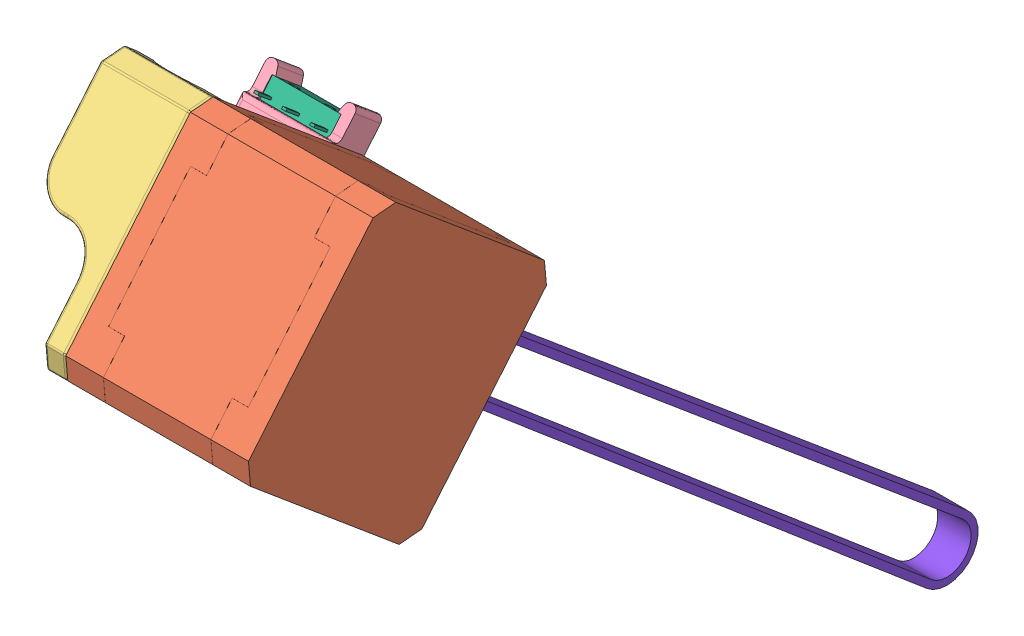
SolidWorks assembly X Stepper Assembly, configuration Default. Lengths in mm.
Overall size (57.11 160.28 210.05).
15 component instances, 12 part files, 20 mates.
Components (placement in the parent):
- Timing Gear 15 touth MXL MP-1: Timing Gear 15 touth MXL MP [Valor predeterminado] at origin size (14.3 14.8 14.8)
- Steper Motor 34mm-1: Steper Motor 34mm [Default] at (53 0 0) x (0 0.766371 -0.642398) z (-1 0 0) size (42.1 42.1 49.5)
- X Motor atachment mirror3-1: X Motor atachment mirror3 [Valor predeterminado] at (19 -41.7303 -84.9055) x (0 -0.642398 -0.766371) z (-1 0 0) size (11.1 84.26 17.12)
- X Bridge spacer for endstop-1: X Bridge spacer for endstop [Valor predeterminado] at (19 -20.6422 -23.8215) x (0 0.642398 0.766371) z (-1 0 0) size (9.2 14.43 16.74)
- Endstop Assembly - small-1: Endstop Assembly - small [Default] at (5.9214 9.6342 -22.8905) x (-1 0 0) z (0 -0.766371 0.642398) size (13.8 11.8 5.71)
  - Endstop Actuator 1-1: Endstop Actuator 1 [Default] at (-9.3436 7.5264 -0.1798) size (12.8 2.57 3.6)
  - Enstop Base 1-1: Enstop Base 1 [Default] at (-1.4636 2.6194 0.1552) size (12.83 9.86 5.71)
- X Bridge spacer-1: X Bridge spacer [Valor predeterminado] at (19 -3.8335 11.8254) x (0 -0.132847 -0.991137) z (-1 0 0) size (6.2 6.2 16.74)
- X Belt (MXL)-1: X Belt (MXL) [Default] at (10.1 -178.8916 299.2878) x (0 0.762669 -0.646788) z (1 0 0) size (11.6 200.95 6.2)
- pan head cross recess screw_iso1-1: pan head cross recess screw_iso1 [ISO 7045 - M3 x 25 - Z --- 25N] at (-4.14 -21.8359 -1.9216) x (1 0 0) z (0 0.424638 0.905363) size (27.35 5.6 5.6)
- pan head cross recess screw_iso1-2: pan head cross recess screw_iso1 [ISO 7045 - M3 x 25 - Z --- 25N] at (-4.14 1.9216 -21.8359) x (1 0 0) z (0 0.386405 -0.922329) size (27.35 5.6 5.6)
- hex thin nut chamfered gradeab_iso1-1: hex thin nut chamfered gradeab_iso1 [Hexagon Thin Nut ISO - 4035 - M3 - N] at (5.8002 21.8359 1.9216) x (0 -0.939519 -0.342497) z (1 0 0) size (5.5 6.35 1.8)
- pan cross head_am1-1: pan cross head_am1 [B18.6.7M - M3 x 0.5 x 8 Type I Cross Recessed PHMS --8N] at (-4.14 21.8359 1.9216) x (1 0 0) z (0 0.642398 0.766371) size (10.37 5.6 5.6)
- socket countersunk head screw_am1-1: socket countersunk head screw_am1 [B18.3.5M - 3 x 0.5 x 10 Socket FCHS  -- 10N] at (14.79 21.8359 1.9216) x (1 0 0) z (0 0.642398 0.766371) size (10 5.35 5.35)
- socket countersunk head screw_am1-2: socket countersunk head screw_am1 [B18.3.5M - 3 x 0.5 x 10 Socket FCHS  -- 10N] at (14.79 -1.9216 21.8359) x (1 0 0) z (0 0.157474 -0.987523) size (10 5.35 5.35)
Mates (geometry in assembly coordinates):
- Distância12: distance = 2 mm: plane of Steper Motor 34mm-1 through (17 0 0) normal (-1 0 0); plane of Timing Gear 15 touth MXL MP-1 through (2.2 0 0) normal (-1 0 0)
- Concêntrico37: concentric aligned: cylinder of Timing Gear 15 touth MXL MP-1 through (16.5 0 0) axis (1 0 0) radius 2.5; cylinder of Steper Motor 34mm-1 through (3.5 0 0) axis (1 0 0) radius 2.5
- Distance3: distance = 0.5 mm anti-aligned: plane of Timing Gear 15 touth MXL MP-1 through (16.5 7.4 0) normal (1 0 0); plane of Steper Motor 34mm-1 through (17 0 0) normal (-1 0 0)
- Coincident7871392: coincident anti-aligned: plane of Steper Motor 34mm-1 through (19 2.6096 -29.6546) normal (-1 0 0); plane of X Motor atachment mirror3-1 through (19 -1.9216 21.8359) normal (1 0 0)
- Concentric401189: concentric aligned: cylinder of Steper Motor 34mm-1 through (19 21.8359 1.9216) axis (-1 0 0) radius 1.25; cylinder of X Motor atachment mirror3-1 through (2.26 21.8359 1.9216) axis (-1 0 0) radius 1.6
- Coincident7871398: coincident anti-aligned: plane of X Bridge spacer for endstop-1 through (-4.9184 2.7029 -26.5359) normal (0 0.766371 -0.642398); plane of Endstop Assembly - small-1/Enstop Base 1-1 through (17.065 2.7029 -26.5359) normal (0 -0.766371 0.642398)
- Coincident7871399: coincident anti-aligned: plane of X Bridge spacer for endstop-1 through (17.065 15.1257 -36.9491) normal (-1 0 0); plane of Endstop Assembly - small-1/Enstop Base 1-1 through (17.065 11.0187 -25.5116) normal (1 0 0)
- Coincident7871400: coincident anti-aligned: plane of X Bridge spacer for endstop-1 through (19 -12.3446 -13.9226) normal (0 0.642398 0.766371); plane of Endstop Assembly - small-1/Enstop Base 1-1 through (17.065 7.0827 -30.2072) normal (0 -0.642398 -0.766371)
- Concentric401186: concentric anti-aligned: circle of Steper Motor 34mm-1; circle of X Bridge spacer-1
- Concentric401187: concentric aligned: circle of Steper Motor 34mm-1; cylinder of X Bridge spacer-1 through (2.26 -21.8359 -1.9216) axis (1 0 0) radius 3.1
- Tangent6: tangent: plane of X Belt (MXL)-1 through (3.9 -125.8368 -142.268) normal (0 0.762671 -0.646787); cylinder of Timing Gear 15 touth MXL MP-1 through (16.5 0 0) axis (-1 0 0) radius 3.955
- Concentric401183: concentric: cylinder of X Belt (MXL)-1 through (3.9 0 0) axis (1 0 0) radius 5.255; cylinder of Timing Gear 15 touth MXL MP-1 through (16.5 0 0) axis (-1 0 0) radius 7.4
- Concentric401184: concentric anti-aligned: cylinder of X Belt (MXL)-1 through (3.9 0 0) axis (1 0 0) radius 3.955; cylinder of Timing Gear 15 touth MXL MP-1 through (16.5 0 0) axis (-1 0 0) radius 7.4
- Distance5: distance = 0.7 mm anti-aligned: plane of X Belt (MXL)-1 through (3.9 -122.4048 -145.1786) normal (-1 0 0); plane of Timing Gear 15 touth MXL MP-1 through (3.2 7.4 0) normal (1 0 0)
- Concentric401193: concentric anti-aligned: cylinder of pan head cross recess screw_iso-2 through (-29.54 1.9216 -21.8359) axis (-1 0 0) radius 1.5; cylinder of X Bridge spacer for endstop-1 through (19 1.9216 -21.8359) axis (1 0 0) radius 1.6
- Concentric401194: concentric anti-aligned: cylinder of X Motor atachment mirror3-1 through (2.26 21.8359 1.9216) axis (-1 0 0) radius 1.6; cylinder of hex thin nut chamfered gradeab_iso-1 through (4.0002 21.8359 1.9216) axis (1 0 0) radius 1.25
- Coincident7871402: coincident anti-aligned: plane of X Motor atachment mirror3-1 through (4.0002 -41.7303 -84.9055) normal (1 0 0); plane of hex thin nut chamfered gradeab_iso-1 through (4.0002 22.9235 -1.0618) normal (-1 0 0)
- Coincident7871403: coincident anti-aligned: plane of X Motor atachment mirror3-1 through (7.7 18.7085 2.4714) normal (0 0.939519 0.342497); plane of hex thin nut chamfered gradeab_iso-1 through (4.0002 19.796 -0.512) normal (0 -0.939519 -0.342497)
- Coincident78718914: coincident aligned: cone of X Motor atachment mirror3-1 through (15 21.8359 1.9216) axis (1 0 0); cone of socket countersunk head screw_am-1 through (15.475 21.8359 1.9216) axis (1 0 0)
- Coincident787189121: coincident aligned: cone of X Motor atachment mirror3-1 through (15 -1.9216 21.8359) axis (1 0 0); cone of socket countersunk head screw_am-2 through (15.475 -1.9216 21.8359) axis (1 0 0)
